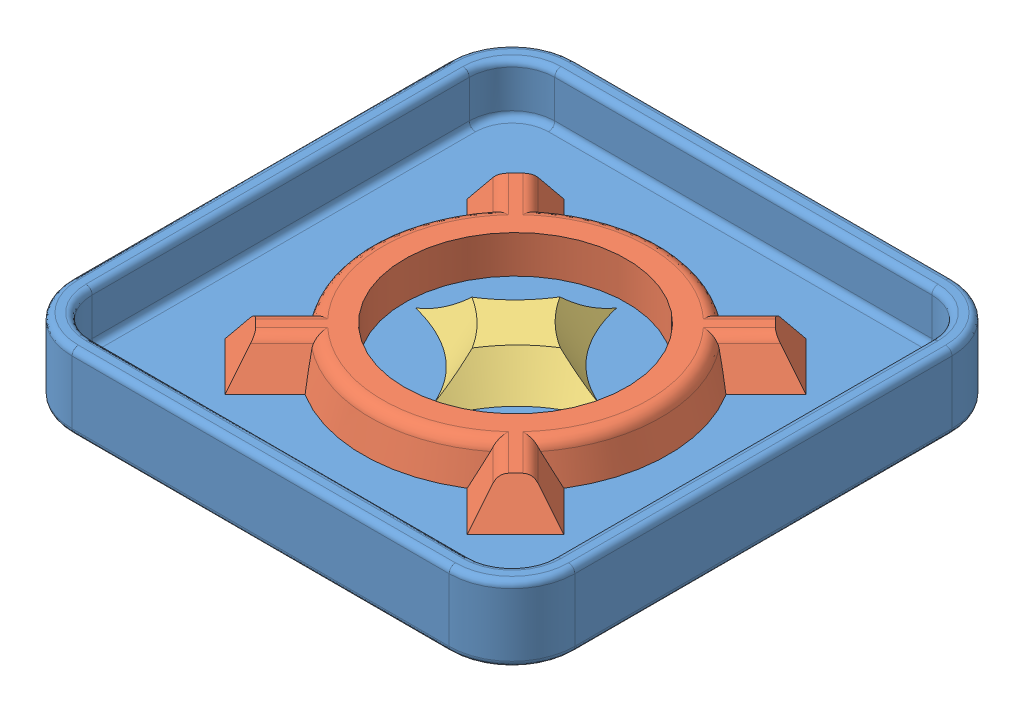
SolidWorks assembly StarGate, configuration Default. Lengths in mm.
Overall size (40 6 40).
3 component instances, 3 part files, 3 mates.
Components (placement in the parent):
- Tile-1: Tile [Default] at (14.3277 17.4348 31.3203) size (40 6 40)
- StarGate_A-1: StarGate_A [Default] at (14.2083 19.4348 30.9203) size (26.96 3.09 26.96)
- StarGate_B-1: StarGate_B [Default] at (14.1789 19.4348 30.8452) size (17.57 3 17.57)
Mates (geometry in assembly coordinates):
- Coincident1: coincident anti-aligned: plane of Tile-1 through (-0.6723 19.4348 46.3203) normal (0 1 0); plane of StarGate_A-1 through (14.2083 19.4348 30.9203) normal (0 -1 0)
- Coincident2: coincident anti-aligned: line of Tile-1 through (29.3277 19.4348 13.4203) axis (-1 0 0); line of StarGate_A-1 through (-3.2917 19.4348 13.4203) axis (1 0 0)
- Coincident3: coincident anti-aligned: plane of Tile-1 through (-0.6723 19.4348 46.3203) normal (0 1 0); plane of StarGate_B-1 through (14.1789 19.4348 30.8452) normal (0 -1 0)
